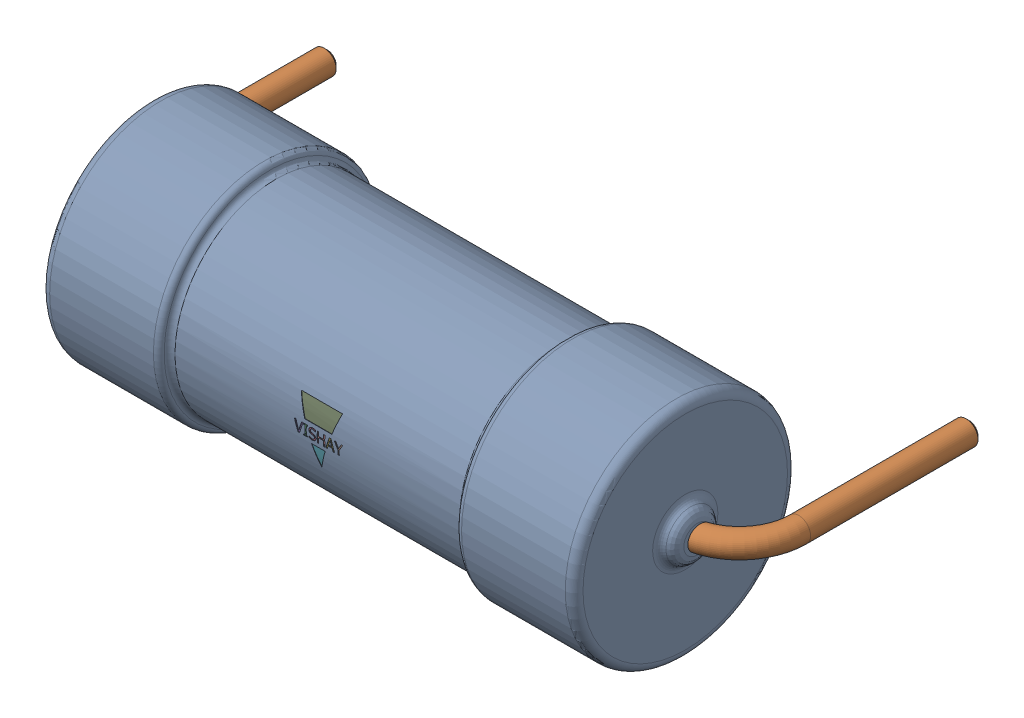
SolidWorks assembly R10.step, configuration Default. Lengths in mm.
Overall size (22.46 7.5 11.5).
4 component instances, 3 part files, 0 mates.
Components (placement in the parent):
- Res_Vishay_AC05000003909JAC00_eec.step-1: Res_Vishay_AC05000003909JAC00_eec.step [Default] at (116.459 12.827 0) size (22.46 7.5 11.5)
  - AC0500000XXXJAC00.step-1: AC0500000XXXJAC00.step [Default] at (-37 0 3.75) size (18.87 7.5 7.5)
  - 1-4.step-1: 1-4.step [Default] at (0 0 -8) x (1 0 0) z (0 -1 0) size (22.46 8.15 0.8)
  - 2-5.step-1: 2-5.step [Default] at (-37 0 3.75) size (1.63 1.9 3.41)
